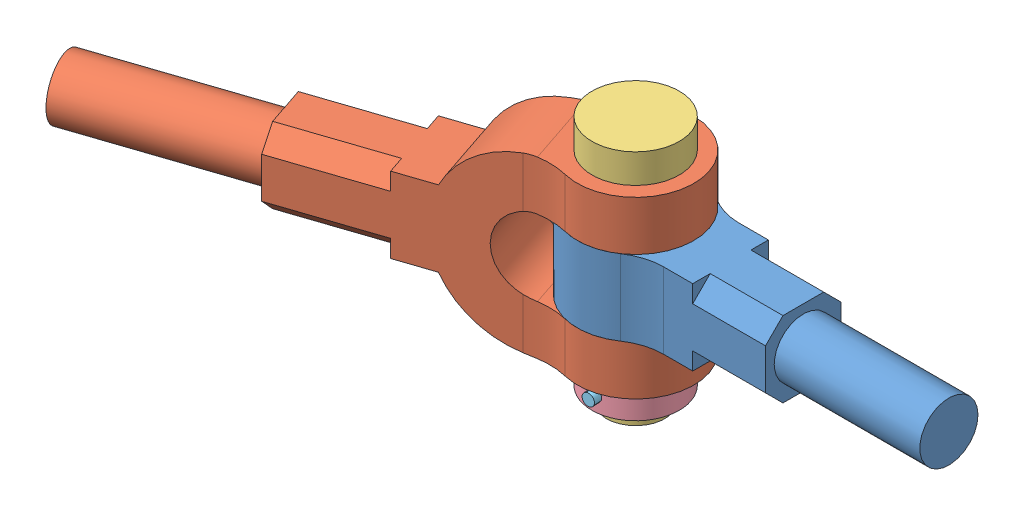
SolidWorks assembly Assem1, configuration Default. Lengths in mm.
Overall size (260.92 85 93.59).
5 component instances, 5 part files, 9 mates.
Components (placement in the parent):
- Part1-2: Part1 [Default] at (27.3469 83.3451 97.5416) x (1 0 0) z (0 -1 0) size (127.61 40 26)
- part 2-1: part 2 [Default] at (-1.8431 83.3451 128.4317) x (-0.948055 0 0.318106) z (0 -1 0) size (175 40 60)
- 3-1: 3 [Default] at (27.3469 38.3451 97.5416) x (0.997679 0 -0.068089) z (0.068089 0 0.997679) size (30 85 30)
- 4-1: 4 [Default] at (27.3469 43.3451 97.5416) x (0.997679 0 -0.068089) z (0.068089 0 0.997679) size (30 10 30)
- 5-1: 5 [Default] at (28.5384 48.3451 115.001) x (-0.068089 0 -0.997679) z (0.832324 0.551371 -0.056804) size (35 5 5)
Mates (geometry in assembly coordinates):
- Concentric1: concentric anti-aligned: cylinder of Part1-2 through (27.3469 70.3451 97.5416) axis (0 1 0) radius 10; cylinder of part 2-1 through (27.3469 151.3451 97.5416) axis (0 -1 0) radius 10
- Coincident1: coincident anti-aligned: plane of Part1-2 through (49.9522 70.3451 64.5416) normal (0 -1 0); plane of part 2-1 through (-1.8431 70.3451 128.4317) normal (0 1 0)
- Concentric2: concentric aligned: cylinder of part 2-1 through (27.3469 151.3451 97.5416) axis (0 -1 0) radius 10; cylinder of 3-1 through (27.3469 113.3451 97.5416) axis (0 -1 0) radius 10
- Coincident2: coincident anti-aligned: plane of part 2-1 through (39.9459 113.3451 72.2184) normal (0 1 0); plane of 3-1 through (27.3469 113.3451 97.5416) normal (0 -1 0)
- Concentric3: concentric aligned: cylinder of 3-1 through (27.3469 113.3451 97.5416) axis (0 -1 0) radius 10; cylinder of 4-1 through (27.3469 53.3451 97.5416) axis (0 -1 0) radius 10
- Coincident4: coincident anti-aligned: plane of part 2-1 through (39.9459 53.3451 72.2184) normal (0 -1 0); plane of 4-1 through (27.3469 53.3451 97.5416) normal (0 1 0)
- Concentric4: concentric anti-aligned: cylinder of 3-1 through (29.3896 48.3451 127.472) axis (-0.068089 0 -0.997679) radius 2; cone of 4-1 through (27.3469 48.3451 97.5416) axis (0.068089 0 0.997679)
- Concentric5: concentric aligned: cone of 4-1 through (27.3469 48.3451 97.5416) axis (0.068089 0 0.997679); cone of 5-1 through (26.1794 48.3451 80.4347) axis (0.068089 0 0.997679)
- Width1: width: plane of 5-1 through (24.7801 50.4307 80.1761) normal (-0.068089 0 -0.997679); plane of 4-1 through (28.5384 48.3451 115.001) normal (0.068089 0 0.997679); cylinder of 5-1 through (27.3469 53.3451 97.5416) axis (0 -1 0) radius 15
